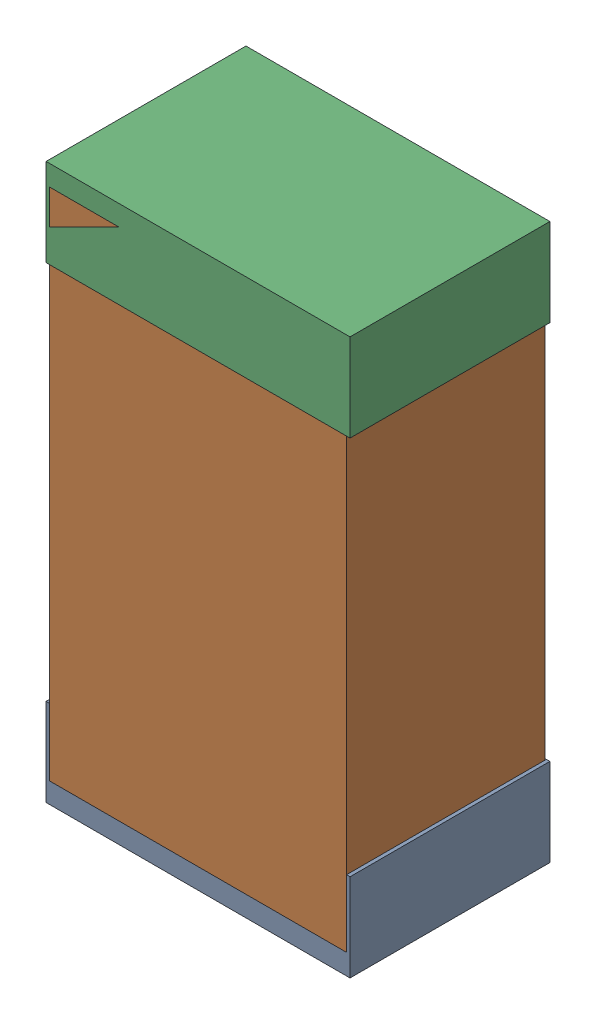
SolidWorks assembly R26Kanaloa_v2.0.0_Motor, configuration Default. Lengths in mm.
Overall size (1.3 2.38 0.85).
6 component instances, 2 part files, 0 mates.
Components (placement in the parent):
- 330415056-1: 330415056 [Default] at (84.074 98.373 -1.9574) size (1.3 0.38 0.85)
  - Extruded_2-1: Extruded_2 [Default] at origin size (1.3 0.38 0.85)
- 334787376-1: 334787376 [Default] at (84.074 99.373 -1.9524) size (1.27 2.2 0.85)
  - Extruded_16-1: Extruded_16 [Default] at origin size (1.27 2.2 0.85)
- 330415056-2: 330415056 [Default] at (84.074 100.373 -1.9574) size (1.3 0.38 0.85)
  - Extruded_2-1: Extruded_2 [Default] at origin size (1.3 0.38 0.85)
